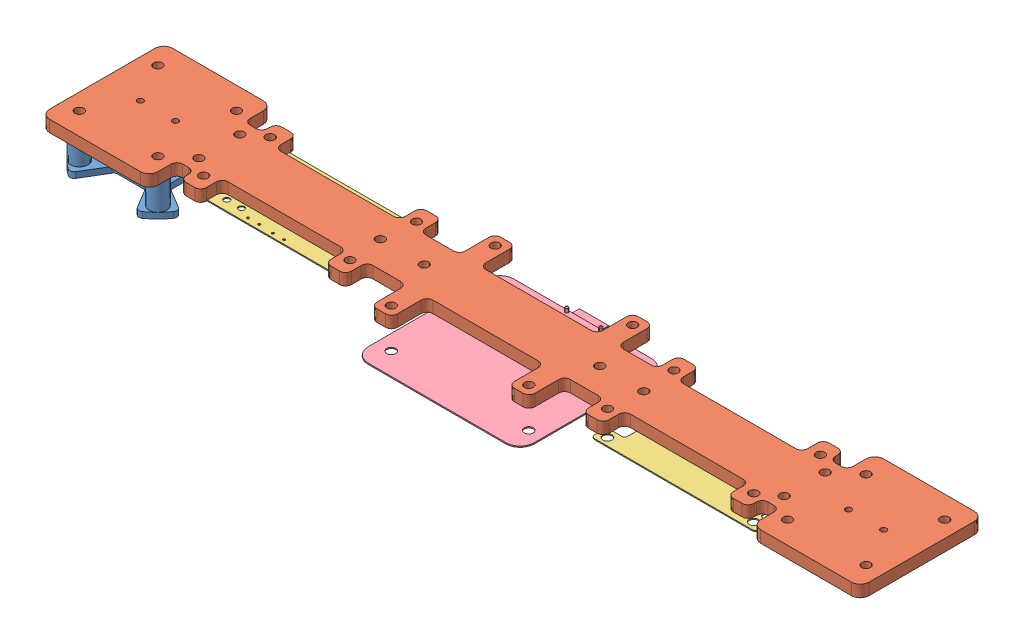
SolidWorks assembly 新机架装配体, configuration 默认. Lengths in mm.
Overall size (292.11 20.05 62.23).
5 component instances, 4 part files, 10 mates.
Components (placement in the parent):
- B2212电机固定-1: B2212电机固定 [默认] at (-121 -10.5 0) x (0.707107 0 -0.707107) z (0 -1 0) size (44 44 12.5)
- 机架-1: 机架 [默认] at origin size (280 4 42.38)
- newPCB-1: newPCB [默认] at (-192.5 -0.1531 -83.129) x (1 0 0) z (0 -1 0) size (56.13 28.07 1.98)
- 双旋翼飞控pcb-1: 双旋翼飞控pcb [默认] at (-104.01 -9.8509 -82.012) x (1 0 0) z (0 -1 0) size (61.41 52.61 11.2)
- newPCB-2: newPCB [默认] at (192.4984 -4.8406 83.1315) x (-1 0 -0.000017) z (0 -1 0) size (56.13 28.07 1.98)
Mates (geometry in assembly coordinates):
- 同心1: concentric: cylinder of assembly; cylinder of assembly; cylinder of B2212电机固定-1 through (-134.435 -12.501 13.435) axis (0 1 0) radius 1.25; cylinder of 机架-1 through (-134.435 0 13.435) axis (0 1 0) radius 1.5
- 同心2: concentric: cylinder of assembly; cylinder of assembly; cylinder of B2212电机固定-1 through (-107.565 -12.501 13.435) axis (0 1 0) radius 1.25; cylinder of 机架-1 through (-107.565 0 13.435) axis (0 1 0) radius 1.5
- 重合1: coincident: circle of assembly; plane of assembly; circle of B2212电机固定-1; plane of 机架-1 through (0 0 0) normal (0 -1 0)
- 平行1: parallel: plane of assembly; plane of assembly; plane of 机架-1 through (0 0 0) normal (0 -1 0); plane of newPCB-1 through (-95.981 0.1924 -13.914) normal (0 1 0)
- 平行2: parallel: plane of assembly; plane of assembly; plane of 机架-1 through (0 0 0) normal (0 -1 0); plane of 双旋翼飞控pcb-1 through (-28.699 -9.4394 -19.656) normal (0 1 0)
- 同心3: concentric: cylinder of assembly; circle of assembly; cylinder of 机架-1 through (-94 0 11.375) axis (0 1 0) radius 1.5; circle of newPCB-1
- 同心4: concentric: cylinder of assembly; cylinder of assembly; cylinder of 机架-1 through (-23.5 -25.3109 17.75) axis (0 1 0) radius 1.5; cylinder of 双旋翼飞控pcb-1 through (-23.5 -9.4394 17.75) axis (0 1 0) radius 1.55
- 同心13: concentric: cylinder of assembly; cylinder of assembly; cylinder of 机架-1 through (-23.5 -25.3109 -17.75) axis (0 1 0) radius 1.5; cylinder of 双旋翼飞控pcb-1 through (-23.5 -9.4394 -17.75) axis (0 1 0) radius 1.55
- 同心14: concentric: cylinder of assembly; cylinder of assembly; cylinder of 机架-1 through (44 -12.2066 -11.375) axis (0 1 0) radius 1.5; cylinder of newPCB-2 through (44 -4.4952 -11.375) axis (0 1 0) radius 1.55
- 同心15: concentric: circle of assembly; circle of assembly; circle of 机架-1; circle of newPCB-2
